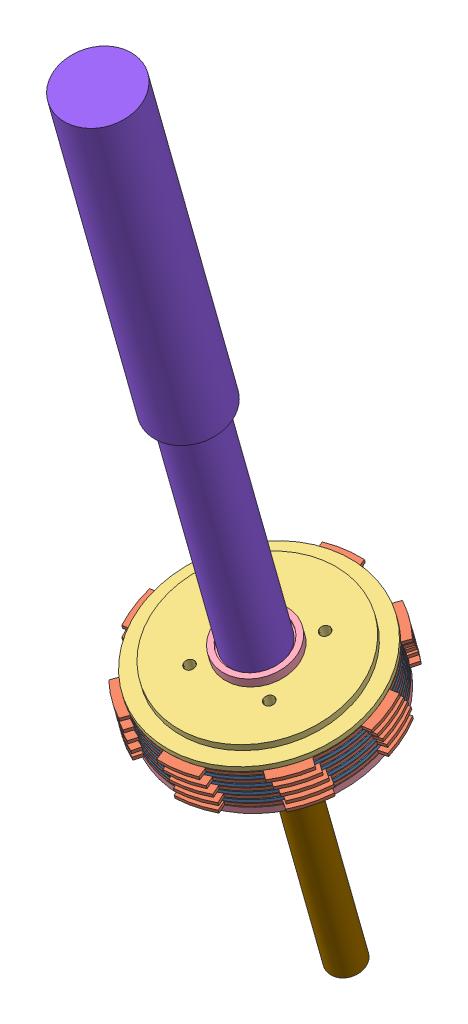
SolidWorks assembly CP, configuration Default. Lengths in mm.
Overall size (164.67 531.37 226.16).
23 component instances, 10 part files, 34 mates.
Components (placement in the parent):
- Part2-1: Part2 [Default] at (312.0021 -75.2293 7.9139) x (0.992392 -0.039184 -0.116713) z (0.074955 0.94435 0.320287) size (109.84 109.84 1.95)
- Part3-1: Part3 [Default] at (312.188 -72.8873 8.7082) x (0.984077 -0.018139 -0.176817) z (0.074955 0.94435 0.320287) size (118.65 118.65 2.96)
- Part4-1: Part4 [Default] at (312.595 -67.7595 10.4474) x (-0.98784 0.026445 0.153207) z (-0.074955 -0.94435 -0.320287) size (109.7 109.7 29.84)
- Part5-1: Part5 [Default] at (310.6761 -91.9349 2.248) x (0.98784 -0.026445 -0.153207) z (0.074955 0.94435 0.320287) size (109.56 109.56 38.35)
- Part2-2: Part2 [Default] at (311.634 -79.8661 6.3413) x (-0.141661 -0.307849 0.94083) z (0.074955 0.94435 0.320287) size (109.84 109.84 1.95)
- Part2-3: Part2 [Default] at (310.898 -89.1396 3.1961) x (0.970923 0.004117 -0.239357) z (0.074955 0.94435 0.320287) size (109.84 109.84 1.95)
- Part2-4: Part2 [Default] at (311.266 -84.5028 4.7687) x (0.995745 -0.053612 -0.074955) z (0.074955 0.94435 0.320287) size (109.84 109.84 1.95)
- Part3-2: Part3 [Default] at (311.4519 -82.1608 5.563) x (-0.846802 0.229895 -0.479661) z (0.074955 0.94435 0.320287) size (118.65 118.65 2.96)
- Part3-3: Part3 [Default] at (310.7158 -91.4343 2.4178) x (0.850869 -0.228059 0.473298) z (0.074955 0.94435 0.320287) size (118.65 118.65 2.96)
- Part3-4: Part3 [Default] at (311.8199 -77.5241 7.1356) x (0.830293 -0.236986 0.504432) z (0.074955 0.94435 0.320287) size (118.65 118.65 2.96)
- Part1-2: Part1 [Default] at (310.1035 -99.1497 -0.199) x (0.98784 -0.026445 -0.153206) z (0.074955 0.94435 0.320287) size (53.6 53.62 8.1)
- part6-2: part6 [Default] at (331.2667 -108.3225 13.8244) x (0.577273 0.220806 -0.78613) z (0.813103 -0.243818 0.528598) size (18.84 22.89 18.68)
- part6-3: part6 [Default] at (293.7288 -107.3176 19.6463) x (0.813103 -0.243818 0.528598) z (-0.577273 -0.220806 0.78613) size (18.84 22.89 18.68)
- part6-4: part6 [Default] at (288.5528 -94.8583 -15.878) x (-0.577273 -0.220806 0.78613) z (-0.813103 0.243818 -0.528598) size (18.84 22.89 18.68)
- part6-5: part6 [Default] at (326.0907 -95.8632 -21.6998) x (-0.813103 0.243818 -0.528598) z (0.577273 0.220806 -0.78613) size (18.84 22.89 18.68)
- Part7-2: Part7 [Default] at (288.7929 -91.8321 -14.8516) x (-0.900865 0.201849 -0.384318) z (-0.42758 -0.259729 0.865861) size (13 30.3 13)
- Part7-3: Part7 [Default] at (293.969 -104.2914 20.6727) x (-0.42758 -0.259729 0.865861) z (0.900865 -0.201849 0.384318) size (13 30.3 13)
- Part7-4: Part7 [Default] at (331.5069 -105.2963 14.8508) x (0.900865 -0.201849 0.384318) z (0.42758 0.259729 -0.865861) size (13 30.3 13)
- Part7-5: Part7 [Default] at (326.3309 -92.837 -20.6735) x (0.42758 0.259729 -0.865861) z (-0.900865 0.201849 -0.384318) size (13 30.3 13)
- Part8-1: Part8 [Default] at (313.1384 -60.9129 12.7694) x (-0.661394 0.287456 -0.692768) z (0.074955 0.94435 0.320287) size (40 40 350)
- Part9-1: Part9 [Default] at (298.1474 -249.783 -51.288) x (-0.978819 0.008312 0.20456) z (0.074955 0.94435 0.320287) size (18 18 200)
- Part1^CP-1: Part1^CP [Default] at origin (virtual)
- Part3-5: Part3 [Default] at (311.0839 -86.7976 3.9904) x (0.508976 0.239971 -0.826654) z (0.074955 0.94435 0.320287) size (118.65 118.65 2.96)
Mates (geometry in assembly coordinates):
- Coincident25: coincident: point of Part5-1; unknown of Part2-3
- Concentric31: concentric anti-aligned: cylinder of Part4-1 through (312.8753 -64.2276 11.6452) axis (-0.074955 -0.94435 -0.320287) radius 19.025; circle of Part5-1
- Concentric32: concentric aligned: circle of Part4-1; cylinder of Part5-1 through (329.4318 -53.7692 -7.4232) axis (-0.074955 -0.94435 -0.320287) radius 7.195
- Concentric39: concentric aligned: circle of Part5-1; circle of Part1-2
- Concentric40: concentric aligned: circle of Part4-1; cylinder of Part1-2 through (326.6922 -88.2852 -19.1297) axis (-0.074955 -0.94435 -0.320287) radius 3.385
- Concentric42: concentric: cone of Part4-1 through (333.9519 -74.4916 25.2986) axis (-0.074955 -0.94435 -0.320287); point of part6-2
- Coincident71: coincident anti-aligned: plane of Part5-1 through (333.3673 -81.8575 22.8003) normal (-0.074955 -0.94435 -0.320287); plane of part6-2 through (340.9282 -90.6169 46.8573) normal (0.074955 0.94435 0.320287)
- Coincident72: coincident anti-aligned: plane of Part1-2 through (310.5112 -94.0124 1.5434) normal (0.074955 0.94435 0.320287); plane of part6-3 through (296.8719 -108.9708 48.8392) normal (-0.074955 -0.94435 -0.320287)
- Concentric47: concentric aligned: cylinder of Part1-2 through (288.8964 -90.5289 -14.4096) axis (-0.074955 -0.94435 -0.320287) radius 6.5; cylinder of Part10-2 through (288.8964 -90.5289 -14.4096) axis (-0.074955 -0.94435 -0.320287) radius 6.5
- Coincident75: coincident anti-aligned: plane of Part1-2 through (288.8964 -90.5289 -14.4096) normal (-0.074955 -0.94435 -0.320287); plane of Part10-2 through (288.8964 -90.5289 -14.4096) normal (0.074955 0.94435 0.320287)
- Concentric48: concentric aligned: circle of Part5-1; circle of Part8-1
- Concentric49: concentric aligned: circle of Part5-1; circle of Part8-1
- Coincident76: coincident anti-aligned: plane of Part5-1 through (313.1384 -60.9129 12.7694) normal (0.074955 0.94435 0.320287); plane of Part8-1 through (313.1384 -60.9129 12.7694) normal (-0.074955 -0.94435 -0.320287)
- Coincident77: coincident anti-aligned: plane of Part8-1 through (313.1384 -60.9129 12.7694) normal (-0.074955 -0.94435 -0.320287); plane of Part9-1 through (313.1384 -60.9129 12.7694) normal (0.074955 0.94435 0.320287)
- Concentric50: concentric anti-aligned: cylinder of Part5-1 through (310.3763 -95.7123 0.9669) axis (0.074955 0.94435 0.320287) radius 9; cylinder of Part9-1 through (313.1384 -60.9129 12.7694) axis (-0.074955 -0.94435 -0.320287) radius 9
- Concentric51: concentric anti-aligned: circle of Part5-1; circle of Part3-3
- Coincident79: coincident anti-aligned: plane of Part5-1 through (310.6761 -91.9349 2.248) normal (0.074955 0.94435 0.320287); plane of Part3-3 through (310.6761 -91.9349 2.248) normal (-0.074955 -0.94435 -0.320287)
- Concentric52: concentric anti-aligned: circle of Part4-1; circle of Part2-3
- Coincident80: coincident anti-aligned: plane of Part2-3 through (310.898 -89.1396 3.1961) normal (-0.074955 -0.94435 -0.320287); plane of Part3-3 through (310.898 -89.1396 3.1961) normal (0.074955 0.94435 0.320287)
- Concentric53: concentric aligned: circle of Part4-1; circle of Part3-5
- Coincident81: coincident anti-aligned: plane of Part2-3 through (311.0441 -87.2981 3.8206) normal (0.074955 0.94435 0.320287); plane of Part3-5 through (311.0441 -87.2981 3.8206) normal (-0.074955 -0.94435 -0.320287)
- Concentric54: concentric anti-aligned: circle of Part4-1; circle of Part2-4
- Coincident82: coincident anti-aligned: plane of Part2-4 through (311.266 -84.5028 4.7687) normal (-0.074955 -0.94435 -0.320287); plane of Part3-5 through (311.266 -84.5028 4.7687) normal (0.074955 0.94435 0.320287)
- Concentric55: concentric aligned: circle of Part2-4; circle of Part3-2
- Coincident83: coincident anti-aligned: plane of Part2-4 through (311.4122 -82.6613 5.3932) normal (0.074955 0.94435 0.320287); plane of Part3-2 through (311.4122 -82.6613 5.3932) normal (-0.074955 -0.94435 -0.320287)
- Concentric56: concentric anti-aligned: circle of Part4-1; circle of Part2-2
- Coincident85: coincident anti-aligned: plane of Part2-2 through (311.634 -79.8661 6.3413) normal (-0.074955 -0.94435 -0.320287); plane of Part3-2 through (311.634 -79.8661 6.3413) normal (0.074955 0.94435 0.320287)
- Concentric57: concentric aligned: circle of Part4-1; circle of Part3-4
- Coincident86: coincident anti-aligned: plane of Part2-2 through (311.7802 -78.0246 6.9658) normal (0.074955 0.94435 0.320287); plane of Part3-4 through (311.7802 -78.0246 6.9658) normal (-0.074955 -0.94435 -0.320287)
- Concentric58: concentric aligned: circle of Part2-1; circle of Part4-1
- Coincident87: coincident anti-aligned: plane of Part2-1 through (312.0021 -75.2293 7.9139) normal (-0.074955 -0.94435 -0.320287); plane of Part3-4 through (312.0021 -75.2293 7.9139) normal (0.074955 0.94435 0.320287)
- Concentric59: concentric aligned: circle of Part3-1; circle of Part4-1
- Coincident88: coincident anti-aligned: plane of Part2-1 through (312.1482 -73.3878 8.5384) normal (0.074955 0.94435 0.320287); plane of Part3-1 through (312.1482 -73.3878 8.5384) normal (-0.074955 -0.94435 -0.320287)
- Coincident89: coincident anti-aligned: plane of Part3-1 through (312.3701 -70.5925 9.4865) normal (0.074955 0.94435 0.320287); plane of Part4-1 through (312.3701 -70.5925 9.4865) normal (-0.074955 -0.94435 -0.320287)
